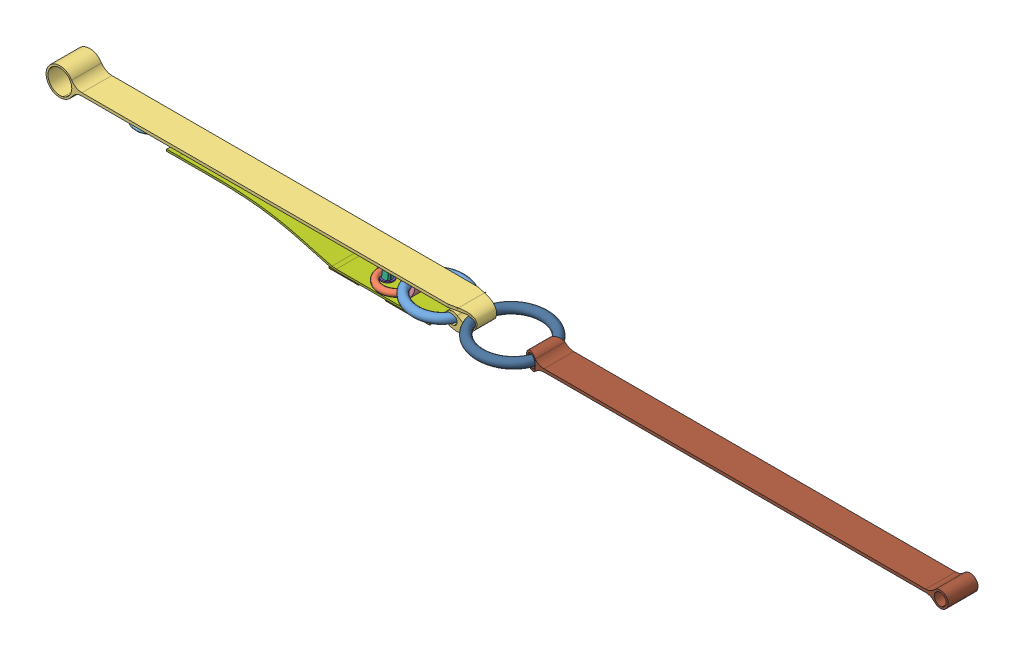
SolidWorks assembly 3-ring_assy_V1, configuration Default. Lengths in mm.
Overall size (479.53 24.52 39.69).
13 component instances, 11 part files, 33 mates.
Components (placement in the parent):
- H3860S_NO3_Ring-1: H3860S_NO3_Ring [Default] at (-51.3677 -8.0145 0) x (0 0 1) z (0.109189 0.994021 0) size (31.35 31.35 4.56)
- H3880S_NO4_Ring-1: H3880S_NO4_Ring [Default] at (-78.0917 -10.3227 0) x (0 0 1) z (0 1 0) size (20.24 20.24 3.37)
- webbing_base_V1-1: webbing_base_V1 [Default] at (-148.7292 0 0) x (1 0 0) z (0 0 -1) size (226.78 20.16 15.88)
- webbing_small_V1-2: webbing_small_V1 [Default] at (-116.3544 -1.524 0) x (1 0 0) z (0 0 -1) size (81.41 12.13 12.7)
- yellow_cord_V1.1-1: yellow_cord_V1.1 [Default] at (-205.5518 -5.8886 0) x (0 1 0) z (0 0 -1) size (13.17 162.26 12)
- nylon_loop_V1-1: nylon_loop_V1 [Default] at (-91.6172 -16.6947 0) x (0 0 1) z (0 -1 0) size (4.82 25.4 15.18)
- grommet_assy-1: grommet_assy [Default] at (-227.0655 159.1333 21.2356) x (0 0 -1) z (0 -1 0) size (19.05 139.7 16.13)
  - webbing_grommet_V1-1: webbing_grommet_V1 [Default] at (21.2356 27.4983 171.1427) size (19.05 139.7 11.24)
  - grommet_V1-1: grommet_V1 [Default] at (21.2356 135.4483 170.5712) x (1 0 0) z (0 -1 0) size (10.16 2.6 10.16)
  - yellow_cord_guide-1: yellow_cord_guide [Default] at (21.2356 159.2608 174.1907) x (1 0 0) z (0 -1 0) size (18.04 4.89 15.88)
- H3840B_NO2_Ring-1: H3840B_NO2_Ring [Default] at (-25.4211 -5.2162 0) x (0.999637 -0.026926 0) z (0.026926 0.999637 0) size (39.69 39.69 4.76)
- webbing_top_V1-3: webbing_top_V1 [Default] at (100.8035 -5.7956 0) size (226.82 8.38 15.88)
- yellow_cord_guide-2: yellow_cord_guide [Default] at (-97.9672 -15.0574 0) x (0 0 -1) z (-1 0 0) size (18.04 4.89 15.88)
Mates (geometry in assembly coordinates):
- Parallel30: parallel: plane of webbing_base_V1-1 through (-148.7292 0 0) normal (0 0 -1); plane of assembly through (0 0 0) normal (0 0 1)
- Coincident83: coincident: plane of webbing_base_V1-1 through (-148.7292 -1.524 0) normal (0 -1 0); plane of webbing_small_V1-2 through (-116.3544 -1.524 0) normal (0 1 0)
- Parallel31: parallel: plane of webbing_base_V1-1 through (-250.3292 -1.524 7.9375) normal (0 0 1); plane of webbing_small_V1-2 through (-154.4544 -2.54 6.35) normal (0 0 1)
- Tangent33: tangent: torus of H3880S_NO4_Ring-1; plane of webbing_small_V1-2 through (-123.1879 -1.7048 0.0803) normal (0 -1 0)
- Angle1: planar angle = 0 rad: cylinder of nylon_loop_V1-1 through (-90.0297 -14.986 0) axis (-1 0 0) radius 1.5875; cylinder of yellow_cord_V1.1-1 through (-96.4019 -15.4224 0) axis (1 0 0) radius 1.5875
- Parallel32: parallel: plane of H3880S_NO4_Ring-1 through (-78.0917 -10.3227 0) normal (0 1 0); plane of assembly through (0 0 0) normal (0 1 0)
- Tangent35: tangent: torus of H3880S_NO4_Ring-1; cylinder of webbing_small_V1-2 through (-78.2544 -10.16 -6.35) axis (0 0 1) radius 1.524
- Tangent37: tangent: torus of H3860S_NO3_Ring-1; cylinder of webbing_small_V1-2 through (-78.2544 -5.08 -6.35) axis (0 0 1) radius 2.54
- Coincident84: coincident: plane of H3880S_NO4_Ring-1 through (-78.0917 -10.3227 0) normal (0 0 1); plane of webbing_small_V1-2 through (-116.3544 -1.524 0) normal (0 0 -1)
- Coincident85: coincident: plane of webbing_base_V1-1 through (-148.7292 0 0) normal (0 0 -1); plane of webbing_small_V1-2 through (-116.3544 -1.524 0) normal (0 0 -1)
- Coincident86: coincident: plane of H3860S_NO3_Ring-1 through (-51.3677 -8.0145 0) normal (0 0 1); plane of H3880S_NO4_Ring-1 through (-78.0917 -10.3227 0) normal (0 0 1)
- Tangent38: tangent: torus of H3860S_NO3_Ring-1; cylinder of webbing_base_V1-1 through (-51.3642 -8.1454 7.9375) axis (0 0 -1) radius 2.413
- Parallel34: parallel: plane of webbing_small_V1-2 through (-116.3544 -2.54 0) normal (0 -1 0); plane of grommet_assy-1/webbing_grommet_V1-1 through (-199.5672 -13.0254 0) normal (0 -1 0)
- Coincident91: coincident: plane of webbing_small_V1-2 through (-116.3544 -2.54 0) normal (0 -1 0); plane of nylon_loop_V1-1 through (-91.6172 -2.54 0.8958) normal (0 1 0)
- Coincident92: coincident: plane of webbing_base_V1-1 through (-148.7292 0 0) normal (0 0 -1); plane of nylon_loop_V1-1 through (-91.6172 -16.6947 0) normal (0 0 1)
- Coincident93: coincident: plane of H3880S_NO4_Ring-1 through (-93.2047 -10.3227 0) normal (1 0 0); plane of nylon_loop_V1-1 through (-93.2047 -16.6947 0) normal (-1 0 0)
- Coincident95: coincident: line of yellow_cord_V1.1-1 through (-96.1522 -15.4224 0) axis (1 0 0); point of nylon_loop_V1-1
- Distance1: distance = 25.4 mm: point of nylon_loop_V1-1; plane of yellow_cord_V1.1-1 through (-66.2172 -15.4224 0) normal (1 0 0)
- Parallel35: parallel: plane of webbing_small_V1-2 through (-116.3544 -2.54 0) normal (0 -1 0); plane of yellow_cord_V1.1-1 through (-205.5518 -5.8886 0) normal (0 1 0)
- Concentric6: concentric: line of nylon_loop_V1-1 through (44.704 -91.6172 -14.6627) axis (0 0 -1); cylinder of grommet_assy-1/grommet_V1-1 through (-91.6172 -13.0254 0) axis (0 1 0) radius 2.3813
- Tangent41: tangent: torus of H3880S_NO4_Ring-1; plane of grommet_assy-1/webbing_grommet_V1-1 through (-199.5672 -12.0094 0) normal (0 1 0)
- Coincident97: coincident: plane of webbing_base_V1-1 through (-148.7292 0 0) normal (0 1 0); plane of assembly through (0 0 0) normal (0 1 0)
- Coincident98: coincident: plane of H3860S_NO3_Ring-1 through (-51.3677 -8.0145 0) normal (0 0 1); plane of assembly through (0 0 0) normal (0 0 1)
- Coincident99: coincident: plane of H3840B_NO2_Ring-1 through (-25.4211 -5.2162 0) normal (0 0 -1); plane of assembly through (0 0 0) normal (0 0 1)
- Tangent43: tangent: cylinder of webbing_base_V1-1 through (-42.883 -4.7148 7.9375) axis (0 0 -1) radius 2.413; torus of H3840B_NO2_Ring-1
- Tangent45: tangent: torus of H3840B_NO2_Ring-1; cylinder of webbing_top_V1-3 through (-8.4165 -5.0336 -7.9375) axis (0 0 1) radius 3.175
- Parallel37: parallel: plane of webbing_small_V1-2 through (-116.3544 -2.54 0) normal (0 -1 0); plane of webbing_top_V1-3 through (100.8035 -5.7956 0) normal (0 -1 0)
- Coincident101: coincident: plane of webbing_base_V1-1 through (-250.3292 -1.524 -7.9375) normal (0 0 -1); plane of webbing_top_V1-3 through (-0.7965 -4.2716 -7.9375) normal (0 0 -1)
- Coincident104: coincident: plane of grommet_assy-1/webbing_grommet_V1-1 through (-199.5672 -13.0254 0) normal (0 -1 0); plane of yellow_cord_guide-2 through (-113.8422 -13.0254 -2.032) normal (0 1 0)
- Coincident105: coincident: plane of grommet_assy-1/webbing_grommet_V1-1 through (-199.5672 -13.0254 -9.525) normal (0 0 -1); plane of yellow_cord_guide-2 through (-113.8422 -14.0414 -9.0208) normal (0 0 -1)
- Perpendicular1: perpendicular: plane of yellow_cord_V1.1-1 through (-205.5518 -5.8886 0) normal (0 0 1); plane of grommet_assy-1/webbing_grommet_V1-1 through (-199.5672 -13.0254 0) normal (0 -1 0)
- Distance2: distance = 14.2875 mm: plane of yellow_cord_guide-2 through (-97.9672 -15.0574 0) normal (1 0 0); plane of grommet_assy-1/yellow_cord_guide-1 through (-83.6797 -15.0574 0) normal (-1 0 0)
- Coincident109: coincident: plane of grommet_assy-1/webbing_grommet_V1-1 through (-199.5672 -12.0094 0) normal (0 0 -1); plane of yellow_cord_guide-2 through (-97.9672 -15.0574 0) normal (0 0 -1)
